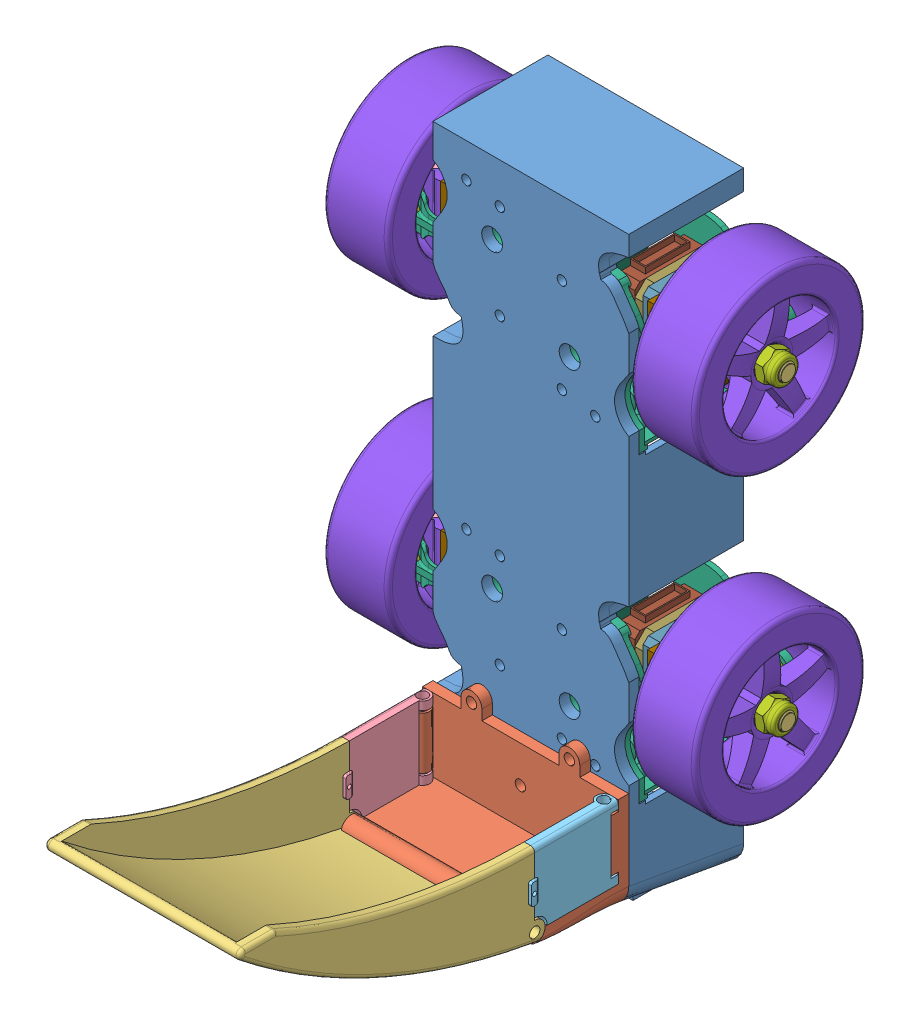
SolidWorks assembly Assembly dolly, configuration Default. Lengths in mm.
Overall size (185.37 297.4 273.69).
154 component instances, 26 part files, 31 mates.
Components (placement in the parent):
- Dolly chassis test-1: Dolly chassis test [Default] at (68.0981 266.9359 270.3999) size (93.68 290 55)
- front assembly-1: front assembly [Default] at (34.906 84.0425 264.6799) x (1 0 0) z (0 -1 0) size (96.68 187.95 76.47) (flexible)
  - Foldable front base-1: Foldable front base [Default] at (80.0311 10.72 74.0587) size (94.83 52.01 59.18)
  - foldable front flap-1: foldable front flap [Default] at (33.1911 55.72 65.5358) x (-1 0 0) z (0 0 -1) size (94.29 145.94 67.36)
  - Foldable front side flap-1: Foldable front side flap [Default] at (-11.1489 19.22 25.4587) x (0 0 1) z (-1 0 0) size (35 43 8.5)
  - Foldable front side flap left-1: Foldable front side flap left [Default] at (77.5311 19.22 60.4587) x (0 0 -1) z (1 0 0) size (35 43 8.5)
- Module Assembly-1: Module Assembly [Default] at (134.5981 240.4359 242.8999) x (0 1 0) z (1 0 0) size (68.25 51.28 97.81)
  - Housing-1: Housing [Default] at origin size (64.25 48.5 67.91)
  - Bearing 12x8-1: Bearing 12x8 [Default] at (0 -18.25 0.75) x (-0.914388 0 0.40484) z (-0.40484 0 -0.914388) size (12 3.5 12)
  - Spindle-1: Spindle [Default] at (0 2 0.75) size (49.04 45 20.5)
  - Spindle base-1: Spindle base [Default] at (0 2 -15.25) x (-1 0 0) z (0 -1 0) size (37.62 3.5 44.8)
  - Encoder-1: Encoder [Défaut] at (0 2 -12.48) x (0 1 0) z (0 0 1) size (28.68 37.25 10.4)
  - Wheel-1: Wheel [Default] at (0 2 -8.55) x (0.929787 0.368098 0) z (0.368098 -0.929787 0) size (81.5 31 81.5) (hidden)
  - Stepper Nema14-1: Stepper Nema14 [Predeterminado] at (4.764 -15.5 -30.1157) x (-1 0 0) z (0 1 0) size (37.8 40 35)
    - nema14_base-1: nema14_base [Predeterminado] at (-12.736 -8.6343 35) size (37.8 9 35)
    - nema14_centro-1: nema14_centro [Predeterminado] at (-12.736 0.3657 35) size (35 4 35)
    - nema14_eje-1: nema14_eje [Predeterminado] at (4.764 -6.6343 17.5) x (0 1 0) z (-0.939004 0 0.343907) size (38 5 5)
    - nema14_techo-1: nema14_techo [Predeterminado] at (-12.736 4.3657 35) size (35 9 35)
  - Servo motor-1: Servo motor [Default] at (-25.7048 26.288 -66.0832) x (0 0 1) z (1 0 0) size (11.5 29.2 32.5) (flexible)
    - TowerPro-SG90-Body-1: TowerPro-SG90-Body [Default] at (13.6721 7.288 30.7048) size (11.5 26 32.5)
    - ServoFinalGear-1: ServoFinalGear [Default] at (13.6721 33.288 25.7048) x (0.607544 0 -0.794286) z (0.794286 0 0.607544) size (4.64 3.2 4.64)
  - Control arm-1: Control arm [Default] at (0 -7.5 -52.4111) x (0.891007 0 0.45399) z (0.45399 0 -0.891007) size (37.9 4.5 7.8)
  - Ball joint assy-1: Ball joint assy [Default] at (-26.7302 -5 -12.8697) x (-0.874356 0 0.485286) z (0.485286 0 0.874356) size (15.43 16.21 22.24) (flexible)
    - Ball-1: Ball [Default] at origin size (5.5 15.11 5.5)
    - Joint-1: Joint [Default] at (-3.8823 13.66 -6.9948) x (0.874356 0 -0.485286) z (0 -1 0) size (5.1 22.6 5.1)
  - Ball joint assy-2: Ball joint assy [Default] at (-26.7302 -5 -66.0308) x (-0.846813 0 0.531891) z (0.531891 0 0.846813) size (16.34 16.21 21.85) (flexible)
    - Ball-1: Ball [Default] at origin size (5.5 15.11 5.5)
    - Joint-1: Joint [Default] at (4.2551 13.66 6.7745) x (-0.846813 0 0.531891) z (0 -1 0) size (5.1 22.6 5.1)
  - Steering rod-1: Steering rod [Default] at (-26.7302 -18.66 -18.4608) x (-0.014502 0.999895 0) z (-0.999895 -0.014502 0) size (3 28.27 3)
  - Wheel adapter-1: Wheel adapter [Default] at (0 2 -13.8175) x (0.291296 -0.956633 0) z (-0.956633 -0.291296 0) size (8.34 40 8.37)
  - Wheel spacer-1: Wheel spacer [Default] at (0 2 12.25) x (0.368098 -0.929787 0) z (0.929787 0.368098 0) size (13.86 8 12)
  - M3x5 din 7984-1: M3x5 din 7984 [Default] at (15.31 20.9 -16.25) x (0.933505 0.358563 0) z (0 0 -1) size (5.5 5.5 7)
  - Housing lid-1: Housing lid [Default] at (0 4 0) x (-1 0 0) z (0 0 1) size (68.25 9.28 69.91)
  - Bearing 12x8-3: Bearing 12x8 [Default] at (0 22.25 0.75) x (-0.914388 0 0.40484) z (0.40484 0 0.914388) size (12 3.5 12)
  - M8 nut-1: M8 nut [Default] at (0 2 16.6825) x (-0.817347 -0.576146 0) z (0 0 1) size (13 16.06 8.5)
  - M3x5 din 7984-2: M3x5 din 7984 [Default] at (15.31 -16.9 -16.25) x (-0.933505 0.358563 0) z (0 0 -1) size (5.5 5.5 7)
  - M3x5 din 7984-3: M3x5 din 7984 [Default] at (-15.31 20.9 -16.25) x (0.933505 -0.358563 0) z (0 0 -1) size (5.5 5.5 7)
  - M3x5 din 7984-4: M3x5 din 7984 [Default] at (-15.31 -16.9 -16.25) x (-0.933505 -0.358563 0) z (0 0 -1) size (5.5 5.5 7)
  - M3x5 din 7984-5: M3x5 din 7984 [Default] at (-13 15 -17.75) x (0.999849 0.017374 0) z (0 0 1) size (5.5 5.5 7)
  - M3x5 din 7984-6: M3x5 din 7984 [Default] at (-13 -11 -17.75) x (-0.999849 0.017374 0) z (0 0 1) size (5.5 5.5 7)
  - M3x5 din 7984-7: M3x5 din 7984 [Default] at (13 15 -17.75) x (0.999849 -0.017374 0) z (0 0 1) size (5.5 5.5 7)
  - M3x5 din 7984-8: M3x5 din 7984 [Default] at (13 -11 -17.75) x (-0.999849 -0.017374 0) z (0 0 1) size (5.5 5.5 7)
- Module Assembly-2: Module Assembly [Default] at (134.5981 95.7859 242.8999) x (0 1 0) z (1 0 0) size (68.25 51.28 97.81)
  - Housing-1: Housing [Default] at origin size (64.25 48.5 67.91)
  - Bearing 12x8-1: Bearing 12x8 [Default] at (0 -18.25 0.75) x (-0.914388 0 0.40484) z (-0.40484 0 -0.914388) size (12 3.5 12)
  - Spindle-1: Spindle [Default] at (0 2 0.75) size (49.04 45 20.5)
  - Spindle base-1: Spindle base [Default] at (0 2 -15.25) x (-1 0 0) z (0 -1 0) size (37.62 3.5 44.8)
  - Encoder-1: Encoder [Défaut] at (0 2 -12.48) x (0 1 0) z (0 0 1) size (28.68 37.25 10.4)
  - Wheel-1: Wheel [Default] at (0 2 -8.55) x (0.929787 0.368098 0) z (0.368098 -0.929787 0) size (81.5 31 81.5) (hidden)
  - Stepper Nema14-1: Stepper Nema14 [Predeterminado] at (4.764 -15.5 -30.1157) x (-1 0 0) z (0 1 0) size (37.8 40 35)
    - nema14_base-1: nema14_base [Predeterminado] at (-12.736 -8.6343 35) size (37.8 9 35)
    - nema14_centro-1: nema14_centro [Predeterminado] at (-12.736 0.3657 35) size (35 4 35)
    - nema14_eje-1: nema14_eje [Predeterminado] at (4.764 -6.6343 17.5) x (0 1 0) z (-0.939004 0 0.343907) size (38 5 5)
    - nema14_techo-1: nema14_techo [Predeterminado] at (-12.736 4.3657 35) size (35 9 35)
  - Servo motor-1: Servo motor [Default] at (-25.7048 26.288 -66.0832) x (0 0 1) z (1 0 0) size (11.5 29.2 32.5) (flexible)
    - TowerPro-SG90-Body-1: TowerPro-SG90-Body [Default] at (13.6721 7.288 30.7048) size (11.5 26 32.5)
    - ServoFinalGear-1: ServoFinalGear [Default] at (13.6721 33.288 25.7048) x (0.607544 0 -0.794286) z (0.794286 0 0.607544) size (4.64 3.2 4.64)
  - Control arm-1: Control arm [Default] at (0 -7.5 -52.4111) x (0.891007 0 0.45399) z (0.45399 0 -0.891007) size (37.9 4.5 7.8)
  - Ball joint assy-1: Ball joint assy [Default] at (-26.7302 -5 -12.8697) x (-0.874356 0 0.485286) z (0.485286 0 0.874356) size (15.43 16.21 22.24) (flexible)
    - Ball-1: Ball [Default] at origin size (5.5 15.11 5.5)
    - Joint-1: Joint [Default] at (-3.8823 13.66 -6.9948) x (0.874356 0 -0.485286) z (0 -1 0) size (5.1 22.6 5.1)
  - Ball joint assy-2: Ball joint assy [Default] at (-26.7302 -5 -66.0308) x (-0.846813 0 0.531891) z (0.531891 0 0.846813) size (16.34 16.21 21.85) (flexible)
    - Ball-1: Ball [Default] at origin size (5.5 15.11 5.5)
    - Joint-1: Joint [Default] at (4.2551 13.66 6.7745) x (-0.846813 0 0.531891) z (0 -1 0) size (5.1 22.6 5.1)
  - Steering rod-1: Steering rod [Default] at (-26.7302 -18.66 -18.4608) x (-0.014502 0.999895 0) z (-0.999895 -0.014502 0) size (3 28.27 3)
  - Wheel adapter-1: Wheel adapter [Default] at (0 2 -13.8175) x (0.291296 -0.956633 0) z (-0.956633 -0.291296 0) size (8.34 40 8.37)
  - Wheel spacer-1: Wheel spacer [Default] at (0 2 12.25) x (0.368098 -0.929787 0) z (0.929787 0.368098 0) size (13.86 8 12)
  - M3x5 din 7984-1: M3x5 din 7984 [Default] at (15.31 20.9 -16.25) x (0.933505 0.358563 0) z (0 0 -1) size (5.5 5.5 7)
  - Housing lid-1: Housing lid [Default] at (0 4 0) x (-1 0 0) z (0 0 1) size (68.25 9.28 69.91)
  - Bearing 12x8-3: Bearing 12x8 [Default] at (0 22.25 0.75) x (-0.914388 0 0.40484) z (0.40484 0 0.914388) size (12 3.5 12)
  - M8 nut-1: M8 nut [Default] at (0 2 16.6825) x (-0.817347 -0.576146 0) z (0 0 1) size (13 16.06 8.5)
  - M3x5 din 7984-2: M3x5 din 7984 [Default] at (15.31 -16.9 -16.25) x (-0.933505 0.358563 0) z (0 0 -1) size (5.5 5.5 7)
  - M3x5 din 7984-3: M3x5 din 7984 [Default] at (-15.31 20.9 -16.25) x (0.933505 -0.358563 0) z (0 0 -1) size (5.5 5.5 7)
  - M3x5 din 7984-4: M3x5 din 7984 [Default] at (-15.31 -16.9 -16.25) x (-0.933505 -0.358563 0) z (0 0 -1) size (5.5 5.5 7)
  - M3x5 din 7984-5: M3x5 din 7984 [Default] at (-13 15 -17.75) x (0.999849 0.017374 0) z (0 0 1) size (5.5 5.5 7)
  - M3x5 din 7984-6: M3x5 din 7984 [Default] at (-13 -11 -17.75) x (-0.999849 0.017374 0) z (0 0 1) size (5.5 5.5 7)
  - M3x5 din 7984-7: M3x5 din 7984 [Default] at (13 15 -17.75) x (0.999849 -0.017374 0) z (0 0 1) size (5.5 5.5 7)
  - M3x5 din 7984-8: M3x5 din 7984 [Default] at (13 -11 -17.75) x (-0.999849 -0.017374 0) z (0 0 1) size (5.5 5.5 7)
- Module Assembly-3: Module Assembly [Default] at (1.5981 95.7859 242.8999) x (0 -1 0) z (-1 0 0) size (68.25 51.28 97.81)
  - Housing-1: Housing [Default] at origin size (64.25 48.5 67.91)
  - Bearing 12x8-1: Bearing 12x8 [Default] at (0 -18.25 0.75) x (-0.914388 0 0.40484) z (-0.40484 0 -0.914388) size (12 3.5 12)
  - Spindle-1: Spindle [Default] at (0 2 0.75) size (49.04 45 20.5)
  - Spindle base-1: Spindle base [Default] at (0 2 -15.25) x (-1 0 0) z (0 -1 0) size (37.62 3.5 44.8)
  - Encoder-1: Encoder [Défaut] at (0 2 -12.48) x (0 1 0) z (0 0 1) size (28.68 37.25 10.4)
  - Wheel-1: Wheel [Default] at (0 2 -8.55) x (0.929787 0.368098 0) z (0.368098 -0.929787 0) size (81.5 31 81.5) (hidden)
  - Stepper Nema14-1: Stepper Nema14 [Predeterminado] at (4.764 -15.5 -30.1157) x (-1 0 0) z (0 1 0) size (37.8 40 35)
    - nema14_base-1: nema14_base [Predeterminado] at (-12.736 -8.6343 35) size (37.8 9 35)
    - nema14_centro-1: nema14_centro [Predeterminado] at (-12.736 0.3657 35) size (35 4 35)
    - nema14_eje-1: nema14_eje [Predeterminado] at (4.764 -6.6343 17.5) x (0 1 0) z (-0.939004 0 0.343907) size (38 5 5)
    - nema14_techo-1: nema14_techo [Predeterminado] at (-12.736 4.3657 35) size (35 9 35)
  - Servo motor-1: Servo motor [Default] at (-25.7048 26.288 -66.0832) x (0 0 1) z (1 0 0) size (11.5 29.2 32.5) (flexible)
    - TowerPro-SG90-Body-1: TowerPro-SG90-Body [Default] at (13.6721 7.288 30.7048) size (11.5 26 32.5)
    - ServoFinalGear-1: ServoFinalGear [Default] at (13.6721 33.288 25.7048) x (0.607544 0 -0.794286) z (0.794286 0 0.607544) size (4.64 3.2 4.64)
  - Control arm-1: Control arm [Default] at (0 -7.5 -52.4111) x (0.891007 0 0.45399) z (0.45399 0 -0.891007) size (37.9 4.5 7.8)
  - Ball joint assy-1: Ball joint assy [Default] at (-26.7302 -5 -12.8697) x (-0.874356 0 0.485286) z (0.485286 0 0.874356) size (15.43 16.21 22.24) (flexible)
    - Ball-1: Ball [Default] at origin size (5.5 15.11 5.5)
    - Joint-1: Joint [Default] at (-3.8823 13.66 -6.9948) x (0.874356 0 -0.485286) z (0 -1 0) size (5.1 22.6 5.1)
  - Ball joint assy-2: Ball joint assy [Default] at (-26.7302 -5 -66.0308) x (-0.846813 0 0.531891) z (0.531891 0 0.846813) size (16.34 16.21 21.85) (flexible)
    - Ball-1: Ball [Default] at origin size (5.5 15.11 5.5)
    - Joint-1: Joint [Default] at (4.2551 13.66 6.7745) x (-0.846813 0 0.531891) z (0 -1 0) size (5.1 22.6 5.1)
  - Steering rod-1: Steering rod [Default] at (-26.7302 -18.66 -18.4608) x (-0.014502 0.999895 0) z (-0.999895 -0.014502 0) size (3 28.27 3)
  - Wheel adapter-1: Wheel adapter [Default] at (0 2 -13.8175) x (0.291296 -0.956633 0) z (-0.956633 -0.291296 0) size (8.34 40 8.37)
  - Wheel spacer-1: Wheel spacer [Default] at (0 2 12.25) x (0.368098 -0.929787 0) z (0.929787 0.368098 0) size (13.86 8 12)
  - M3x5 din 7984-1: M3x5 din 7984 [Default] at (15.31 20.9 -16.25) x (0.933505 0.358563 0) z (0 0 -1) size (5.5 5.5 7)
  - Housing lid-1: Housing lid [Default] at (0 4 0) x (-1 0 0) z (0 0 1) size (68.25 9.28 69.91)
  - Bearing 12x8-3: Bearing 12x8 [Default] at (0 22.25 0.75) x (-0.914388 0 0.40484) z (0.40484 0 0.914388) size (12 3.5 12)
  - M8 nut-1: M8 nut [Default] at (0 2 16.6825) x (-0.817347 -0.576146 0) z (0 0 1) size (13 16.06 8.5)
  - M3x5 din 7984-2: M3x5 din 7984 [Default] at (15.31 -16.9 -16.25) x (-0.933505 0.358563 0) z (0 0 -1) size (5.5 5.5 7)
  - M3x5 din 7984-3: M3x5 din 7984 [Default] at (-15.31 20.9 -16.25) x (0.933505 -0.358563 0) z (0 0 -1) size (5.5 5.5 7)
  - M3x5 din 7984-4: M3x5 din 7984 [Default] at (-15.31 -16.9 -16.25) x (-0.933505 -0.358563 0) z (0 0 -1) size (5.5 5.5 7)
  - M3x5 din 7984-5: M3x5 din 7984 [Default] at (-13 15 -17.75) x (0.999849 0.017374 0) z (0 0 1) size (5.5 5.5 7)
  - M3x5 din 7984-6: M3x5 din 7984 [Default] at (-13 -11 -17.75) x (-0.999849 0.017374 0) z (0 0 1) size (5.5 5.5 7)
  - M3x5 din 7984-7: M3x5 din 7984 [Default] at (13 15 -17.75) x (0.999849 -0.017374 0) z (0 0 1) size (5.5 5.5 7)
  - M3x5 din 7984-8: M3x5 din 7984 [Default] at (13 -11 -17.75) x (-0.999849 -0.017374 0) z (0 0 1) size (5.5 5.5 7)
- Module Assembly-5: Module Assembly [Default] at (1.5981 240.4359 242.8999) x (0 -1 0) z (-1 0 0) size (68.25 51.28 97.81)
  - Housing-1: Housing [Default] at origin size (64.25 48.5 67.91)
  - Bearing 12x8-1: Bearing 12x8 [Default] at (0 -18.25 0.75) x (-0.914388 0 0.40484) z (-0.40484 0 -0.914388) size (12 3.5 12)
  - Spindle-1: Spindle [Default] at (0 2 0.75) size (49.04 45 20.5)
  - Spindle base-1: Spindle base [Default] at (0 2 -15.25) x (-1 0 0) z (0 -1 0) size (37.62 3.5 44.8)
  - Encoder-1: Encoder [Défaut] at (0 2 -12.48) x (0 1 0) z (0 0 1) size (28.68 37.25 10.4)
  - Wheel-1: Wheel [Default] at (0 2 -8.55) x (0.929787 0.368098 0) z (0.368098 -0.929787 0) size (81.5 31 81.5) (hidden)
  - Stepper Nema14-1: Stepper Nema14 [Predeterminado] at (4.764 -15.5 -30.1157) x (-1 0 0) z (0 1 0) size (37.8 40 35)
    - nema14_base-1: nema14_base [Predeterminado] at (-12.736 -8.6343 35) size (37.8 9 35)
    - nema14_centro-1: nema14_centro [Predeterminado] at (-12.736 0.3657 35) size (35 4 35)
    - nema14_eje-1: nema14_eje [Predeterminado] at (4.764 -6.6343 17.5) x (0 1 0) z (-0.939004 0 0.343907) size (38 5 5)
    - nema14_techo-1: nema14_techo [Predeterminado] at (-12.736 4.3657 35) size (35 9 35)
  - Servo motor-1: Servo motor [Default] at (-25.7048 26.288 -66.0832) x (0 0 1) z (1 0 0) size (11.5 29.2 32.5) (flexible)
    - TowerPro-SG90-Body-1: TowerPro-SG90-Body [Default] at (13.6721 7.288 30.7048) size (11.5 26 32.5)
    - ServoFinalGear-1: ServoFinalGear [Default] at (13.6721 33.288 25.7048) x (0.607544 0 -0.794286) z (0.794286 0 0.607544) size (4.64 3.2 4.64)
  - Control arm-1: Control arm [Default] at (0 -7.5 -52.4111) x (0.891007 0 0.45399) z (0.45399 0 -0.891007) size (37.9 4.5 7.8)
  - Ball joint assy-1: Ball joint assy [Default] at (-26.7302 -5 -12.8697) x (-0.874356 0 0.485286) z (0.485286 0 0.874356) size (15.43 16.21 22.24) (flexible)
    - Ball-1: Ball [Default] at origin size (5.5 15.11 5.5)
    - Joint-1: Joint [Default] at (-3.8823 13.66 -6.9948) x (0.874356 0 -0.485286) z (0 -1 0) size (5.1 22.6 5.1)
  - Ball joint assy-2: Ball joint assy [Default] at (-26.7302 -5 -66.0308) x (-0.846813 0 0.531891) z (0.531891 0 0.846813) size (16.34 16.21 21.85) (flexible)
    - Ball-1: Ball [Default] at origin size (5.5 15.11 5.5)
    - Joint-1: Joint [Default] at (4.2551 13.66 6.7745) x (-0.846813 0 0.531891) z (0 -1 0) size (5.1 22.6 5.1)
  - Steering rod-1: Steering rod [Default] at (-26.7302 -18.66 -18.4608) x (-0.014502 0.999895 0) z (-0.999895 -0.014502 0) size (3 28.27 3)
  - Wheel adapter-1: Wheel adapter [Default] at (0 2 -13.8175) x (0.291296 -0.956633 0) z (-0.956633 -0.291296 0) size (8.34 40 8.37)
  - Wheel spacer-1: Wheel spacer [Default] at (0 2 12.25) x (0.368098 -0.929787 0) z (0.929787 0.368098 0) size (13.86 8 12)
  - M3x5 din 7984-1: M3x5 din 7984 [Default] at (15.31 20.9 -16.25) x (0.933505 0.358563 0) z (0 0 -1) size (5.5 5.5 7)
  - Housing lid-1: Housing lid [Default] at (0 4 0) x (-1 0 0) z (0 0 1) size (68.25 9.28 69.91)
  - Bearing 12x8-3: Bearing 12x8 [Default] at (0 22.25 0.75) x (-0.914388 0 0.40484) z (0.40484 0 0.914388) size (12 3.5 12)
  - M8 nut-1: M8 nut [Default] at (0 2 16.6825) x (-0.817347 -0.576146 0) z (0 0 1) size (13 16.06 8.5)
  - M3x5 din 7984-2: M3x5 din 7984 [Default] at (15.31 -16.9 -16.25) x (-0.933505 0.358563 0) z (0 0 -1) size (5.5 5.5 7)
  - M3x5 din 7984-3: M3x5 din 7984 [Default] at (-15.31 20.9 -16.25) x (0.933505 -0.358563 0) z (0 0 -1) size (5.5 5.5 7)
  - M3x5 din 7984-4: M3x5 din 7984 [Default] at (-15.31 -16.9 -16.25) x (-0.933505 -0.358563 0) z (0 0 -1) size (5.5 5.5 7)
  - M3x5 din 7984-5: M3x5 din 7984 [Default] at (-13 15 -17.75) x (0.999849 0.017374 0) z (0 0 1) size (5.5 5.5 7)
  - M3x5 din 7984-6: M3x5 din 7984 [Default] at (-13 -11 -17.75) x (-0.999849 0.017374 0) z (0 0 1) size (5.5 5.5 7)
  - M3x5 din 7984-7: M3x5 din 7984 [Default] at (13 15 -17.75) x (0.999849 -0.017374 0) z (0 0 1) size (5.5 5.5 7)
  - M3x5 din 7984-8: M3x5 din 7984 [Default] at (13 -11 -17.75) x (-0.999849 -0.017374 0) z (0 0 1) size (5.5 5.5 7)
- Wheel-1: Wheel [Default] at (126.0481 95.7859 244.8999) x (0 0.929787 0.368098) z (0 0.368098 -0.929787) size (81.5 31 81.5)
- Wheel-2: Wheel [Default] at (126.0481 240.4359 244.8999) x (0 0.146111 0.989268) z (0 0.989268 -0.146111) size (81.5 31 81.5)
- Wheel-3: Wheel [Default] at (10.1481 240.4359 244.8999) x (0 -0.783676 -0.62117) z (0 0.62117 -0.783676) size (81.5 31 81.5)
- Wheel-4: Wheel [Default] at (10.1481 95.7859 244.8999) x (0 -0.929787 0.368098) z (0 -0.368098 -0.929787) size (81.5 31 81.5)
Mates (geometry in assembly coordinates):
- Coincident1: coincident: plane of Dolly chassis test-1 through (68.0981 266.9359 275.3999) normal (0 0 1); plane of front assembly-1/Foldable front base-1 through (114.937 9.9838 275.3999) normal (0 0 -1)
- Coincident2: coincident: plane of Dolly chassis test-1 through (170.7855 0.2859 220.3999) normal (0 -0.984808 0.173648); plane of front assembly-1/Foldable front base-1 through (114.937 9.9838 275.3999) normal (0 -0.984808 0.173648)
- Coincident3: coincident: plane of Dolly chassis test-1 through (114.937 122.2859 275.3999) normal (1 0 0); plane of front assembly-1/Foldable front base-1 through (114.937 9.9838 320.3999) normal (1 0 0)
- Parallel1: parallel: plane of Dolly chassis test-1 through (21.2593 122.2859 275.3999) normal (-1 0 0); plane of front assembly-1/Foldable front side flap-1 through (21.257 58.5838 283.8999) normal (-1 0 0)
- Parallel2: parallel: plane of Dolly chassis test-1 through (114.937 122.2859 275.3999) normal (1 0 0); plane of front assembly-1/Foldable front side flap left-1 through (114.937 23.5838 283.8999) normal (1 0 0)
- Parallel3: parallel: plane of Dolly chassis test-1 through (68.0981 266.9359 275.3999) normal (0 0 1); plane of front assembly-1/foldable front flap-1 through (109.937 28.5838 320.3999) normal (0 0 -1)
- Coincident16: coincident: plane of Dolly chassis test-1 through (68.0981 266.9359 270.3999) normal (0 0 -1); plane of Module Assembly-5/Housing lid-1 through (1.5981 240.4359 270.3999) normal (0 0 1)
- Concentric1: concentric: cylinder of Dolly chassis test-1 through (49.5593 255.5359 280.3999) axis (0 0 -1) radius 5; cylinder of Module Assembly-5/Housing lid-1 through (49.5593 255.5359 260.3999) axis (0 0 1) radius 5
- Coincident17: coincident: plane of Dolly chassis test-1 through (21.2593 266.9359 275.3999) normal (-1 0 0); plane of Module Assembly-5/Housing lid-1 through (21.2593 240.4359 267.8999) normal (-1 0 0)
- Coincident18: coincident: plane of Dolly chassis test-1 through (68.0981 266.9359 270.3999) normal (0 0 -1); plane of Module Assembly-1/Housing lid-1 through (134.5981 240.4359 270.3999) normal (0 0 1)
- Concentric2: concentric: cylinder of Dolly chassis test-1 through (86.637 225.3359 280.3999) axis (0 0 -1) radius 5; cylinder of Module Assembly-1/Housing lid-1 through (86.637 225.3359 260.3999) axis (0 0 1) radius 5
- Coincident19: coincident: plane of Dolly chassis test-1 through (114.937 266.9359 275.3999) normal (1 0 0); plane of Module Assembly-1/Housing lid-1 through (114.937 240.4359 267.8999) normal (1 0 0)
- Coincident20: coincident: plane of Dolly chassis test-1 through (68.0981 266.9359 270.3999) normal (0 0 -1); plane of Module Assembly-3/Housing lid-1 through (1.5981 95.7859 270.3999) normal (0 0 1)
- Concentric3: concentric: cylinder of Dolly chassis test-1 through (49.5593 110.8859 280.3999) axis (0 0 -1) radius 5; cylinder of Module Assembly-3/Housing lid-1 through (49.5593 110.8859 260.3999) axis (0 0 1) radius 5
- Coincident21: coincident: plane of Dolly chassis test-1 through (21.2593 266.9359 275.3999) normal (-1 0 0); plane of Module Assembly-3/Housing lid-1 through (21.2593 95.7859 267.8999) normal (-1 0 0)
- Concentric4: concentric: cylinder of Dolly chassis test-1 through (86.637 80.6859 280.3999) axis (0 0 -1) radius 5; cylinder of Module Assembly-2/Housing lid-1 through (86.637 80.6859 260.3999) axis (0 0 1) radius 5
- Coincident22: coincident: plane of Dolly chassis test-1 through (68.0981 266.9359 270.3999) normal (0 0 -1); plane of Module Assembly-2/Housing lid-1 through (134.5981 95.7859 270.3999) normal (0 0 1)
- Coincident23: coincident: plane of Dolly chassis test-1 through (114.937 122.2859 275.3999) normal (1 0 0); plane of Module Assembly-2/Housing lid-1 through (114.937 95.7859 267.8999) normal (1 0 0)
- Concentric5: concentric: cylinder of Module Assembly-2/Wheel adapter-1 through (120.7806 95.7859 244.8999) axis (-1 0 0) radius 4; cylinder of Wheel-1 through (126.0481 95.7859 244.8999) axis (1 0 0) radius 4
- Concentric7: concentric: cylinder of Module Assembly-2/Wheel adapter-1 through (120.7806 95.7859 244.8999) axis (-1 0 0) radius 4; cylinder of Wheel-1 through (126.0481 95.7859 244.8999) axis (1 0 0) radius 4
- Coincident29: coincident: plane of Module Assembly-2/Wheel spacer-1 through (138.8481 93.2356 251.3417) normal (0 0.146111 0.989268); plane of Wheel-1 through (146.8481 93.2356 251.3417) normal (0 -0.146111 -0.989268)
- Coincident30: coincident: plane of Module Assembly-2/Wheel spacer-1 through (146.8481 95.7859 244.8999) normal (1 0 0); plane of Wheel-1 through (146.8481 95.7859 244.8999) normal (-1 0 0)
- Concentric8: concentric: cylinder of Module Assembly-1/Wheel adapter-1 through (120.7806 240.4359 244.8999) axis (-1 0 0) radius 4; cylinder of Wheel-2 through (126.0481 240.4359 244.8999) axis (1 0 0) radius 4
- Coincident31: coincident: plane of Module Assembly-1/Wheel spacer-1 through (138.8481 237.8856 251.3417) normal (0 0.146111 0.989268); plane of Wheel-2 through (146.8481 237.8856 251.3417) normal (0 -0.146111 -0.989268)
- Coincident32: coincident: plane of Module Assembly-1/Wheel spacer-1 through (146.8481 240.4359 244.8999) normal (1 0 0); plane of Wheel-2 through (146.8481 240.4359 244.8999) normal (-1 0 0)
- Concentric9: concentric: cylinder of Module Assembly-5/Wheel adapter-1 through (15.4156 240.4359 244.8999) axis (1 0 0) radius 4; cylinder of Wheel-3 through (10.1481 240.4359 244.8999) axis (-1 0 0) radius 4
- Coincident33: coincident: plane of Module Assembly-5/Wheel spacer-1 through (-2.6519 242.9861 251.3417) normal (0 -0.146111 0.989268); plane of Wheel-3 through (-10.6519 242.9861 251.3417) normal (0 0.146111 -0.989268)
- Coincident34: coincident: plane of Module Assembly-5/Wheel spacer-1 through (-10.6519 240.4359 244.8999) normal (-1 0 0); plane of Wheel-3 through (-10.6519 240.4359 244.8999) normal (1 0 0)
- Concentric10: concentric: cylinder of Module Assembly-3/Wheel adapter-1 through (15.4156 95.7859 244.8999) axis (1 0 0) radius 4; cylinder of Wheel-4 through (10.1481 95.7859 244.8999) axis (-1 0 0) radius 4
- Coincident35: coincident: plane of Module Assembly-3/Wheel spacer-1 through (-2.6519 98.3361 251.3417) normal (0 -0.146111 0.989268); plane of Wheel-4 through (-10.6519 98.3361 251.3417) normal (0 0.146111 -0.989268)
- Coincident38: coincident: plane of Module Assembly-3/Wheel spacer-1 through (-10.6519 95.7859 244.8999) normal (-1 0 0); plane of Wheel-4 through (-10.6519 95.7859 244.8999) normal (1 0 0)
